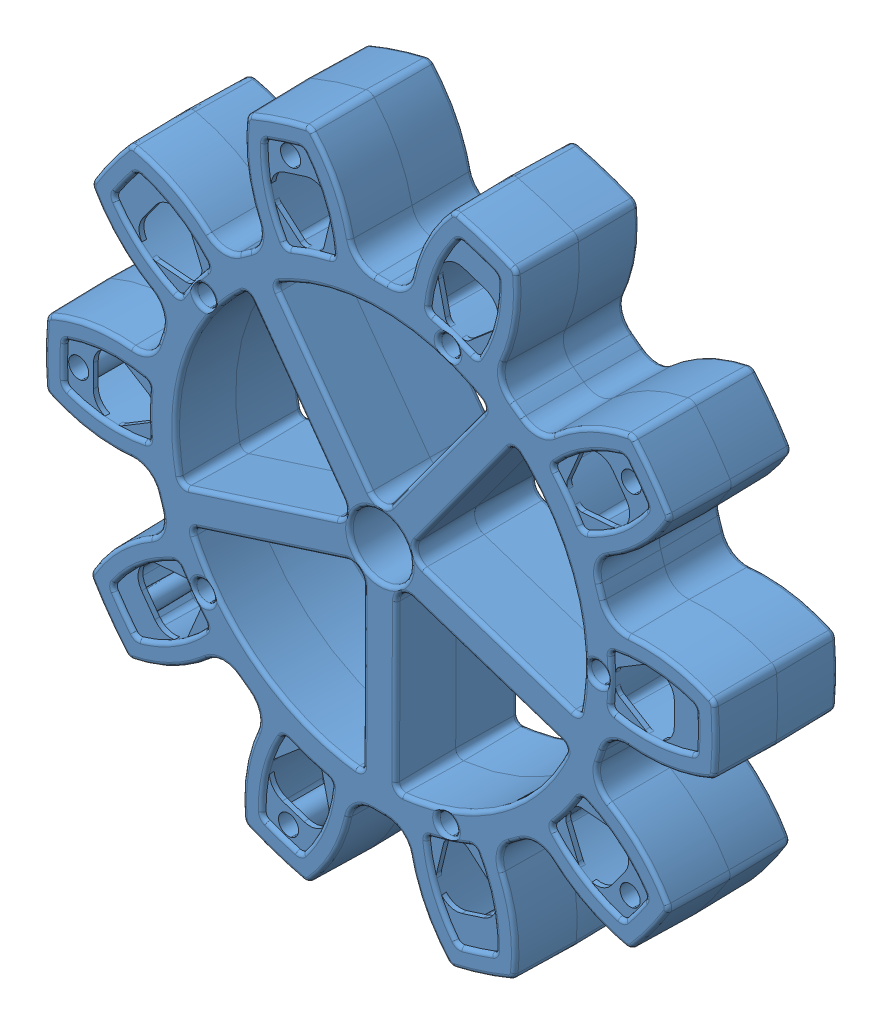
SolidWorks assembly Gear Gampiece, configuration Default. Lengths in mm.
Overall size (282.2 275.37 50.81).
22 component instances, 2 part files, 0 mates.
Components (placement in the parent):
- ip-3302 10T gear-1: ip-3302 10T gear [Default] at origin size (280.29 273.41 28.58)
- ip-3302 10T gear-2: ip-3302 10T gear [Default] x (-0.999975 0.007024 0) z (0 0 -1) size (280.29 273.41 28.58)
- am-1291 screw_90190A196-1: am-1291 screw_90190A196 [Default] at (-90.6774 0.3185 -5.969) x (-0.923728 -0.383049 0) z (0 0 -1) size (8.18 8.18 18.8)
- am-1291 screw_90190A196-2: am-1291 screw_90190A196 [Default] at (-102.4824 75.0091 -4.3538) x (-0.923728 -0.383049 0) z (0 0 -1) size (8.18 8.18 18.8)
- am-1291 screw_90190A196-3: am-1291 screw_90190A196 [Default] at (-126.9992 0.446 4.3538) size (8.18 8.18 18.8)
- am-1291 screw_90190A196-4: am-1291 screw_90190A196 [Default] at (-73.1724 53.5565 5.969) size (8.18 8.18 18.8)
- am-1291 screw_90190A196-5: am-1291 screw_90190A196 [Default] at (-27.718 86.3378 -5.969) x (-0.649749 0.760149 0) z (0 0 -1) size (8.18 8.18 18.8)
- am-1291 screw_90190A196-6: am-1291 screw_90190A196 [Default] at (73.5468 53.0412 -5.969) x (0.522161 0.852847 0) z (0 0 -1) size (8.18 8.18 18.8)
- am-1291 screw_90190A196-7: am-1291 screw_90190A196 [Default] at (73.1724 -53.5565 -5.969) x (0.972462 -0.233061 0) z (0 0 -1) size (8.18 8.18 18.8)
- am-1291 screw_90190A196-8: am-1291 screw_90190A196 [Default] at (-28.3237 -86.141 -5.969) x (0.078854 -0.996886 0) z (0 0 -1) size (8.18 8.18 18.8)
- am-1291 screw_90190A196-9: am-1291 screw_90190A196 [Default] at (39.6691 120.6456 -4.3538) x (-0.649749 0.760149 0) z (0 0 -1) size (8.18 8.18 18.8)
- am-1291 screw_90190A196-10: am-1291 screw_90190A196 [Default] at (126.9992 -0.446 -4.3538) x (0.522161 0.852847 0) z (0 0 -1) size (8.18 8.18 18.8)
- am-1291 screw_90190A196-11: am-1291 screw_90190A196 [Default] at (38.8207 -120.9213 -4.3538) x (0.972462 -0.233061 0) z (0 0 -1) size (8.18 8.18 18.8)
- am-1291 screw_90190A196-12: am-1291 screw_90190A196 [Default] at (-103.0067 -74.2874 -4.3538) x (0.078854 -0.996886 0) z (0 0 -1) size (8.18 8.18 18.8)
- am-1291 screw_90190A196-13: am-1291 screw_90190A196 [Default] at (-38.8207 120.9213 4.3538) x (0.309017 -0.951057 0) z (0 0 1) size (8.18 8.18 18.8)
- am-1291 screw_90190A196-14: am-1291 screw_90190A196 [Default] at (103.0067 74.2874 4.3538) x (-0.809017 -0.587785 0) z (0 0 1) size (8.18 8.18 18.8)
- am-1291 screw_90190A196-15: am-1291 screw_90190A196 [Default] at (102.4824 -75.0091 4.3538) x (-0.809017 0.587785 0) z (0 0 1) size (8.18 8.18 18.8)
- am-1291 screw_90190A196-16: am-1291 screw_90190A196 [Default] at (-39.6691 -120.6456 4.3538) x (0.309017 0.951057 0) z (0 0 1) size (8.18 8.18 18.8)
- am-1291 screw_90190A196-17: am-1291 screw_90190A196 [Default] at (28.3237 86.141 5.969) x (0.309017 -0.951057 0) z (0 0 1) size (8.18 8.18 18.8)
- am-1291 screw_90190A196-18: am-1291 screw_90190A196 [Default] at (90.6774 -0.3185 5.969) x (-0.809017 -0.587785 0) z (0 0 1) size (8.18 8.18 18.8)
- am-1291 screw_90190A196-19: am-1291 screw_90190A196 [Default] at (27.718 -86.3378 5.969) x (-0.809017 0.587785 0) z (0 0 1) size (8.18 8.18 18.8)
- am-1291 screw_90190A196-20: am-1291 screw_90190A196 [Default] at (-73.5468 -53.0412 5.969) x (0.309017 0.951057 0) z (0 0 1) size (8.18 8.18 18.8)
